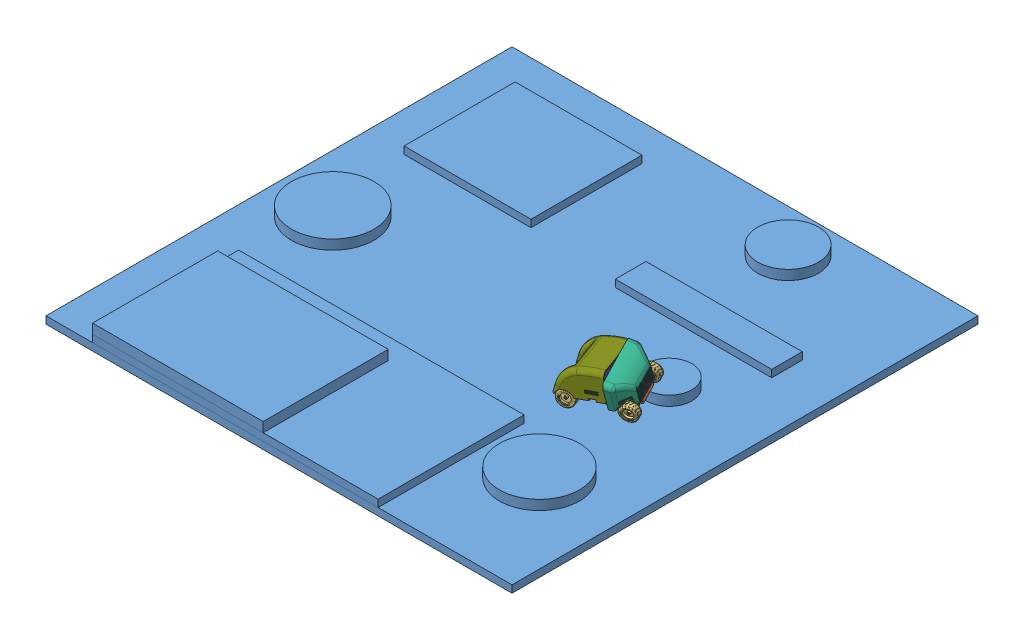
SolidWorks assembly Course Test, configuration Default. Lengths in mm.
Overall size (1219.2 143.11 1219.2).
94 component instances, 26 part files, 3 mates.
Components (placement in the parent):
- Simple Course-1: Simple Course [Default] at (-611.8105 263.1042 144.095) size (1219.2 63.5 1219.2)
- Full Assembly-1: Full Assembly [Default] at (-310.943 323.7713 217.3831) x (0.34202 0 0.939693) z (-0.935314 -0.096423 0.340426) size (150.69 125.08 173.6)
  - Scout Rear End-1: Scout Rear End [Default-_flexible1] at (35.9328 -37.7856 6.7097) size (131.62 97.6 114.89) (flexible)
    - Rear Baseplate-1: Rear Baseplate [Default] at (-42.1312 28.0774 12.7174) size (120.65 1.65 101.6)
    - Pololu Wheel Assembly-1: Pololu Wheel Assembly [Default-_flexible9] at (7.6153 33.3292 58.7651) x (0 0 1) z (1 0 0) size (42.46 78.6 70.03) (flexible)
      - Pololu 49x19 Wheel-1: Pololu 49x19 Wheel [Default] at (-19.8703 11.8393 2.4418) size (42.46 42.56 19)
      - Pololu Extended Micro Metal Bracket-1: Pololu Extended Micro Metal Bracket [Default] at (-19.8703 6.8393 -18.4366) size (26.6 18.17 26.04)
      - Pololu 298-1 Motor-1: Pololu 298-1 Motor [Default] at (-19.8703 11.8393 -25.1366) x (0 0 -1) z (0 1 0) size (35.87 12 10)
    - Pololu Wheel Assembly-2: Pololu Wheel Assembly [Default-_flexible10] at (-91.8778 33.3292 19.0244) x (0 0 -1) z (-1 0 0) size (42.46 78.6 70.03) (flexible)
      - Pololu 49x19 Wheel-1: Pololu 49x19 Wheel [Default] at (-19.8703 11.8393 2.4418) size (42.46 42.56 19)
      - Pololu Extended Micro Metal Bracket-1: Pololu Extended Micro Metal Bracket [Default] at (-19.8703 6.8393 -18.4366) size (26.6 18.17 26.04)
      - Pololu 298-1 Motor-1: Pololu 298-1 Motor [Default] at (-19.8703 11.8393 -25.1366) x (0 0 -1) z (0 1 0) size (35.87 12 10)
    - Socket Head Cap Screw_AI-1: Socket Head Cap Screw_AI [HX-SHCS 0.086-56x0.4375x0.4375-N] at (-77.6912 31.9128 47.8948) x (0 -1 0) z (-0.381305 0 -0.924449) size (13.3 3.56 3.56)
    - Socket Head Cap Screw_AI-2: Socket Head Cap Screw_AI [HX-SHCS 0.086-56x0.4375x0.4375-N] at (-77.6912 31.9128 29.8948) x (0 -1 0) z (0 0 1) size (13.3 3.56 3.56)
    - Socket Head Cap Screw_AI-3: Socket Head Cap Screw_AI [HX-SHCS 0.086-56x0.4375x0.4375-N] at (-6.5712 31.9128 29.8948) x (0 -1 0) z (0 0 1) size (13.3 3.56 3.56)
    - Socket Head Cap Screw_AI-4: Socket Head Cap Screw_AI [HX-SHCS 0.086-56x0.4375x0.4375-N] at (-6.5712 31.9128 47.8948) x (0 -1 0) z (0 0 1) size (13.3 3.56 3.56)
    - Mounting Block-1: Mounting Block [Default] at (-42.1312 34.8084 -38.8462) x (-1 0 0) z (0 0 -1) size (22.23 10.17 19.05)
    - Side IR Mount-3: Side IR Mount [Default] at (-88.5751 48.7784 -43.2912) size (6.35 38.1 46.99)
    - Side IR Mount-4: Side IR Mount [Default] at (4.3127 48.7784 3.6988) x (-1 0 0) z (0 0 -1) size (6.35 38.1 46.99)
    - gp2d12-4: gp2d12 [Default] at (5.0747 48.7784 -19.7962) x (0 0 1) z (1 0 0) size (44.5 18.9 13.5)
    - 4000mAh 7.4V Battery Pack-1: 4000mAh 7.4V Battery Pack [Default] at (-42.1312 46.8734 -10.9062) x (0 0 -1) z (1 0 0) size (34.29 34.29 63.5)
    - mmc90136A465-1: mmc90136A465 [Default] at (7.0747 48.7784 -1.2962) x (0 -1 0) z (0 0 1) size (6.62 6.16 6.63)
    - mmc90136A465-2: mmc90136A465 [Default] at (7.0747 48.7784 -38.2962) x (0 -1 0) z (0 0 1) size (6.62 6.16 6.63)
    - mmc90136A465-3: mmc90136A465 [Default] at (-91.3371 48.7784 -38.2962) x (0 -0.381849 0.924225) z (0 -0.924225 -0.381849) size (6.62 6.16 6.63)
    - mmc90136A465-4: mmc90136A465 [Default] at (-91.3371 48.7784 -1.2962) x (0 -0.381849 0.924225) z (0 -0.924225 -0.381849) size (6.62 6.16 6.63)
    - Socket Button Head Cap Screw_AI-1: Socket Button Head Cap Screw_AI [SBHCSCREW 0.086-56x0.125-HX-N] at (8.6688 26.909 -38.8462) x (0 1 0) z (0 0 1) size (4.34 4.17 4.17)
    - Socket Button Head Cap Screw_AI-2: Socket Button Head Cap Screw_AI [SBHCSCREW 0.086-56x0.125-HX-N] at (-92.9312 26.909 -38.8462) x (0 1 0) z (0 0 1) size (4.34 4.17 4.17)
    - Socket Button Head Cap Screw_AI-3: Socket Button Head Cap Screw_AI [SBHCSCREW 0.086-56x0.125-HX-N] at (-92.9312 26.909 -0.7462) x (0 1 0) z (0 0 1) size (4.34 4.17 4.17)
    - Socket Button Head Cap Screw_AI-4: Socket Button Head Cap Screw_AI [SBHCSCREW 0.086-56x0.125-HX-N] at (8.6688 26.909 -0.7462) x (0 1 0) z (0 0 1) size (4.34 4.17 4.17)
    - Socket Countersunk Head Cap Screw_AI2-1: Socket Countersunk Head Cap Screw_AI2 [SCHCSCREW 0.112-40x0.25x0.25-HX-N] at (-50.3862 28.0619 -44.5612) x (0 1 0) z (-0.806365 0 0.591418) size (6.35 6.29 6.29)
    - Socket Countersunk Head Cap Screw_AI2-2: Socket Countersunk Head Cap Screw_AI2 [SCHCSCREW 0.112-40x0.25x0.25-HX-N] at (-50.3862 28.0619 -33.1312) x (0 1 0) z (0 0 1) size (6.35 6.29 6.29)
    - Socket Countersunk Head Cap Screw_AI2-3: Socket Countersunk Head Cap Screw_AI2 [SCHCSCREW 0.112-40x0.25x0.25-HX-N] at (-33.8762 28.0619 -33.1312) x (0 1 0) z (0 0 1) size (6.35 6.29 6.29)
    - Socket Countersunk Head Cap Screw_AI2-4: Socket Countersunk Head Cap Screw_AI2 [SCHCSCREW 0.112-40x0.25x0.25-HX-N] at (-33.8762 28.0619 -44.5612) x (0 1 0) z (0 0 1) size (6.35 6.29 6.29)
    - Main PCB-1: Main PCB [Default] at (-42.357 67.8284 -19.0109) (suppressed, hidden)
    - XBEE Pro-1: XBEE Pro [Défaut] at (3.3895 71.9686 -30.0445) x (1 0 0) z (0 1 0) (suppressed, hidden)
    - Rear Battery Strap-2: Rear Battery Strap [Default] at (-42.1312 52.7662 -28.0512) size (92.89 12.7 6.35)
    - Socket Button Head Cap Screw_AI-5: Socket Button Head Cap Screw_AI [SBHCSCREW 0.086-56x0.125-HX-N] at (-86.6447 59.1162 -31.2262) x (-1 0 0) z (0 0 1) size (4.34 4.17 4.17)
    - Socket Button Head Cap Screw_AI-6: Socket Button Head Cap Screw_AI [SBHCSCREW 0.086-56x0.125-HX-N] at (2.3823 59.1162 -31.2262) x (1 0 0) z (0 -0.924225 -0.381849) size (4.34 4.17 4.17)
    - GP2Y0D810 Sensor-1: GP2Y0D810 Sensor [Default] at (-94.9417 37.9643 -19.7962) x (0 0 1) z (-0.766044 0.642788 0) size (22.86 11.11 8.89)
    - gp2d12-5: gp2d12 [Default] at (-89.3371 48.7784 -19.7962) x (0 0 -1) z (-1 0 0) size (44.5 18.9 13.5)
    - GP2Y0D810 Sensor-2: GP2Y0D810 Sensor [Default] at (10.6792 37.9643 -19.7962) x (0 0 1) z (-0.766044 -0.642788 0) size (22.86 11.11 8.89)
    - Rear Shell-1: Rear Shell [Default] at (-42.1312 29.7284 65.9288) x (0 0 -1) z (1 0 0) size (114.3 68.08 131.62)
    - Inteface Plate-1: Inteface Plate [Default] at (-42.1312 62.2721 -48.3712) size (127 65.09 1.65)
  - Scout Front End-1: Scout Front End [Default] at (55.6715 -72.6412 -62.0375) x (0.972194 -0.234179 0) z (0 0 1) size (131.64 96.95 57.9)
    - Front Baseplate-1: Front Baseplate [Default] at (-76.4634 46.5072 -32.0242) size (120.65 1.65 50.8)
    - Pololu Wheel Assembly-1: Pololu Wheel Assembly [Default-_flexible3] at (-26.7168 51.7591 2.1802) x (0 0 1) z (1 0 0) size (42.46 78.6 70.03) (flexible)
      - Pololu 49x19 Wheel-1: Pololu 49x19 Wheel [Default] at (-19.8703 11.8393 2.4418) size (42.46 42.56 19)
      - Pololu Extended Micro Metal Bracket-1: Pololu Extended Micro Metal Bracket [Default] at (-19.8703 6.8393 -18.4366) size (26.6 18.17 26.04)
      - Pololu 298-1 Motor-1: Pololu 298-1 Motor [Default] at (-19.8703 11.8393 -25.1366) x (0 0 -1) z (0 1 0) size (35.87 12 10)
    - Pololu Wheel Assembly-2: Pololu Wheel Assembly [Default-_flexible4] at (-126.21 51.7591 -37.5605) x (0 0 -1) z (-1 0 0) size (42.46 78.6 70.03) (flexible)
      - Pololu 49x19 Wheel-1: Pololu 49x19 Wheel [Default] at (-19.8703 11.8393 2.4418) size (42.46 42.56 19)
      - Pololu Extended Micro Metal Bracket-1: Pololu Extended Micro Metal Bracket [Default] at (-19.8703 6.8393 -18.4366) size (26.6 18.17 26.04)
      - Pololu 298-1 Motor-1: Pololu 298-1 Motor [Default] at (-19.8703 11.8393 -25.1366) x (0 0 -1) z (0 1 0) size (35.87 12 10)
    - Socket Head Cap Screw_AI-1: Socket Head Cap Screw_AI [HX-SHCS 0.086-56x0.4375x0.4375-N] at (-112.0234 50.3426 -8.6902) x (0 -1 0) z (0.989468 0 0.144748) size (13.3 3.56 3.56)
    - Socket Head Cap Screw_AI-2: Socket Head Cap Screw_AI [HX-SHCS 0.086-56x0.4375x0.4375-N] at (-40.9034 50.3426 -26.6902) x (0 -1 0) z (0.390166 0 -0.920744) size (13.3 3.56 3.56)
    - Socket Head Cap Screw_AI-3: Socket Head Cap Screw_AI [HX-SHCS 0.086-56x0.4375x0.4375-N] at (-40.9034 50.3426 -8.6902) x (0 -1 0) z (0.700957 0 0.713204) size (13.3 3.56 3.56)
    - Socket Head Cap Screw_AI-4: Socket Head Cap Screw_AI [HX-SHCS 0.086-56x0.4375x0.4375-N] at (-112.0234 50.3426 -26.6902) x (0 -1 0) z (-0.920661 0 -0.390363) size (13.3 3.56 3.56)
    - Mounting Block-1: Mounting Block [Default] at (-76.4634 53.2382 9.2508) size (22.23 10.17 19.05)
    - gp2d12-2: gp2d12 [Default] at (-76.4634 67.9702 -19.3242) x (1 0 0) z (0 0 -1) size (44.5 18.9 13.5)
    - gp2d12-3: gp2d12 [Default] at (-36.6376 67.9702 -2.9934) x (0.707107 0 0.707107) z (0.707107 0 -0.707107) size (44.5 18.9 13.5)
    - gp2d12-4: gp2d12 [Default] at (-116.2892 67.9702 -2.9934) x (0.707107 0 -0.707107) z (-0.707107 0 -0.707107) size (44.5 18.9 13.5)
    - Front IR Mount-1: Front IR Mount [Default] at (-76.4634 61.6202 -19.3242) size (110.93 28.52 37)
    - Bumper-2: Bumper [Default] at (-76.4634 36.9822 -26.9442) x (-1 0 0) z (0 0 -1) size (50.8 9.53 6.35)
    - mmc90136A465-1: mmc90136A465 [Default] at (-104.6219 67.9702 -17.4891) x (0.5 0.707107 -0.5) z (-0.5 0.707107 0.5) size (6.62 6.16 6.63)
    - mmc90136A465-2: mmc90136A465 [Default] at (-130.7849 67.9702 8.6739) x (0.5 0.707107 -0.5) z (-0.5 0.707107 0.5) size (6.62 6.16 6.63)
    - mmc90136A465-3: mmc90136A465 [Default] at (-48.3049 67.9702 -17.4891) x (0.5 -0.707107 0.5) z (0.5 0.707107 0.5) size (6.62 6.16 6.63)
    - mmc90136A465-4: mmc90136A465 [Default] at (-22.1419 67.9702 8.6739) x (0.5 -0.707107 0.5) z (0.5 0.707107 0.5) size (6.62 6.16 6.63)
    - mmc90136A465-5: mmc90136A465 [Default] at (-57.9634 67.9702 -21.3242) x (1 0 0) z (0 1 0) size (6.62 6.16 6.63)
    - mmc90136A465-6: mmc90136A465 [Default] at (-94.9634 67.9702 -21.3242) x (1 0 0) z (0 1 0) size (6.62 6.16 6.63)
    - Sensor PCB-1: Sensor PCB [Default] at (-76.463 60.02 -17.973) size (110.8 1.6 35.94)
    - Sensor PCB Standoff-1: Sensor PCB Standoff [Default] at (-103.3504 48.1582 39.1442) size (7.33 17.45 6.58)
    - Sensor PCB Standoff-2: Sensor PCB Standoff [Default] at (-3.2231 48.1582 39.1442) size (7.33 17.45 6.58)
    - Socket Countersunk Head Cap Screw_AI2-1: Socket Countersunk Head Cap Screw_AI2 [SCHCSCREW 0.112-40x0.25x0.25-HX-N] at (-68.2084 46.5072 3.5358) x (0 1 0) z (0 0 1) size (6.35 6.29 6.29)
    - Socket Countersunk Head Cap Screw_AI2-2: Socket Countersunk Head Cap Screw_AI2 [SCHCSCREW 0.112-40x0.25x0.25-HX-N] at (-84.7184 46.5072 3.5358) x (0 1 0) z (0 0 1) size (6.35 6.29 6.29)
    - Socket Countersunk Head Cap Screw_AI2-3: Socket Countersunk Head Cap Screw_AI2 [SCHCSCREW 0.112-40x0.25x0.25-HX-N] at (-84.7184 46.5072 14.9658) x (0 1 0) z (0 0 1) size (6.35 6.29 6.29)
    - Socket Countersunk Head Cap Screw_AI2-4: Socket Countersunk Head Cap Screw_AI2 [SCHCSCREW 0.112-40x0.25x0.25-HX-N] at (-68.2084 46.5072 14.9658) x (0 1 0) z (0.335002 0 0.942218) size (6.35 6.29 6.29)
    - Socket Button Head Cap Screw_AI-1: Socket Button Head Cap Screw_AI [SBHCSCREW 0.086-56x0.25-HX-N] at (-126.5267 62.7886 13.7099) x (0 -1 0) z (-0.546944 0 0.837169) size (7.52 4.17 4.17)
    - Socket Button Head Cap Screw_AI-2: Socket Button Head Cap Screw_AI [SBHCSCREW 0.086-56x0.25-HX-N] at (-99.5859 62.7886 -13.2309) x (0 -1 0) z (0 0 1) size (7.52 4.17 4.17)
    - Socket Button Head Cap Screw_AI-3: Socket Button Head Cap Screw_AI [SBHCSCREW 0.086-56x0.25-HX-N] at (-53.3401 62.7886 -13.2309) x (0 -1 0) z (0 0 1) size (7.52 4.17 4.17)
    - Socket Button Head Cap Screw_AI-4: Socket Button Head Cap Screw_AI [SBHCSCREW 0.086-56x0.25-HX-N] at (-26.3994 62.7886 13.7099) x (0 -1 0) z (0.705183 0 0.709025) size (7.52 4.17 4.17)
    - Sensor PCB-2: Sensor PCB [Default] at (-76.463 76.6824 -17.973) size (110.8 1.6 35.94)
    - Socket Button Head Cap Screw_AI-6: Socket Button Head Cap Screw_AI [SBHCSCREW 0.086-56x0.188-HX-N] at (-99.5859 79.451 -13.2309) x (0 -1 0) z (0.836581 0 0.547843) size (5.94 4.17 4.17)
    - Socket Button Head Cap Screw_AI-9: Socket Button Head Cap Screw_AI [SBHCSCREW 0.086-56x0.188-HX-N] at (-53.3401 79.451 -13.2309) x (0 -1 0) z (0.836581 0 0.547843) size (5.94 4.17 4.17)
    - Socket Button Head Cap Screw_AI-10: Socket Button Head Cap Screw_AI [SBHCSCREW 0.086-56x0.188-HX-N] at (-126.5267 79.451 13.7099) x (0 -1 0) z (-0.886365 0 0.462987) size (5.94 4.17 4.17)
    - Socket Button Head Cap Screw_AI-11: Socket Button Head Cap Screw_AI [SBHCSCREW 0.086-56x0.188-HX-N] at (-26.3994 79.451 13.7099) x (0 -1 0) z (-0.895952 0 0.444151) size (5.94 4.17 4.17)
    - LED Dome-1: LED Dome [Default] at (-96.5883 78.2826 -4.7508) size (12.7 12.7 12.7)
    - LED Dome-2: LED Dome [Default] at (-55.903 78.2826 -4.7508) size (12.7 12.7 12.7)
    - gp2d12-5: gp2d12 [Default] at (-76.4634 54.6582 -4.5542) x (1 0 0) z (0 0 -1) size (44.5 18.9 13.5)
    - GP2Y0D810 Sensor-1: GP2Y0D810 Sensor [Default] at (-76.4634 48.1582 -24.8487) size (22.86 11.11 8.89)
    - Socket Head Cap Screw_AI-5: Socket Head Cap Screw_AI [HX-SHCS 0.086-56x0.188x0.188-N] at (-61.2234 50.3426 -29.9922) x (0 -1 0) z (-0.920661 0 -0.390363) size (6.96 3.56 3.56)
    - Socket Head Cap Screw_AI-6: Socket Head Cap Screw_AI [HX-SHCS 0.086-56x0.188x0.188-N] at (-91.7034 50.3426 -29.9922) x (0 -1 0) z (-0.920661 0 -0.390363) size (6.96 3.56 3.56)
    - Front Shell-1: Front Shell [Default] at (-76.4634 48.1582 133.0758) x (0 0 -1) z (1 0 0) size (51.56 67.64 131.64)
    - Inteface Plate-1: Inteface Plate [Default] at (-76.4634 80.702 17.1248) size (127 65.09 1.65)
  - 6655k13 Thrust Washers-1: 6655k13 Thrust Washers [Default] at (-6.1984 -2.9772 -42.4616) x (0 0 -1) z (1 0 0) size (4.9 14.15 14.15)
Mates (geometry in assembly coordinates):
- Parallel1: parallel: plane of Simple Course-1 through (-2.2105 282.1542 -465.505) normal (0 1 0); line of Full Assembly-1/Scout Rear End-1/Rear Baseplate-1
- Distance2: distance = 21 mm: axis of Full Assembly-1/Scout Rear End-1/Pololu Wheel Assembly-1/Pololu 49x19 Wheel-1; plane of Simple Course-1 through (-2.2105 282.1542 -465.505) normal (0 1 0)
- Angle2: planar angle = 5.061455 rad aligned: plane of Full Assembly-1/Scout Rear End-1/Rear Shell-1 through (-292.3194 315.3933 273.2731) normal (0.34202 0 0.939693); plane of Simple Course-1 through (-2.2105 282.1542 753.695) normal (1 0 0)
